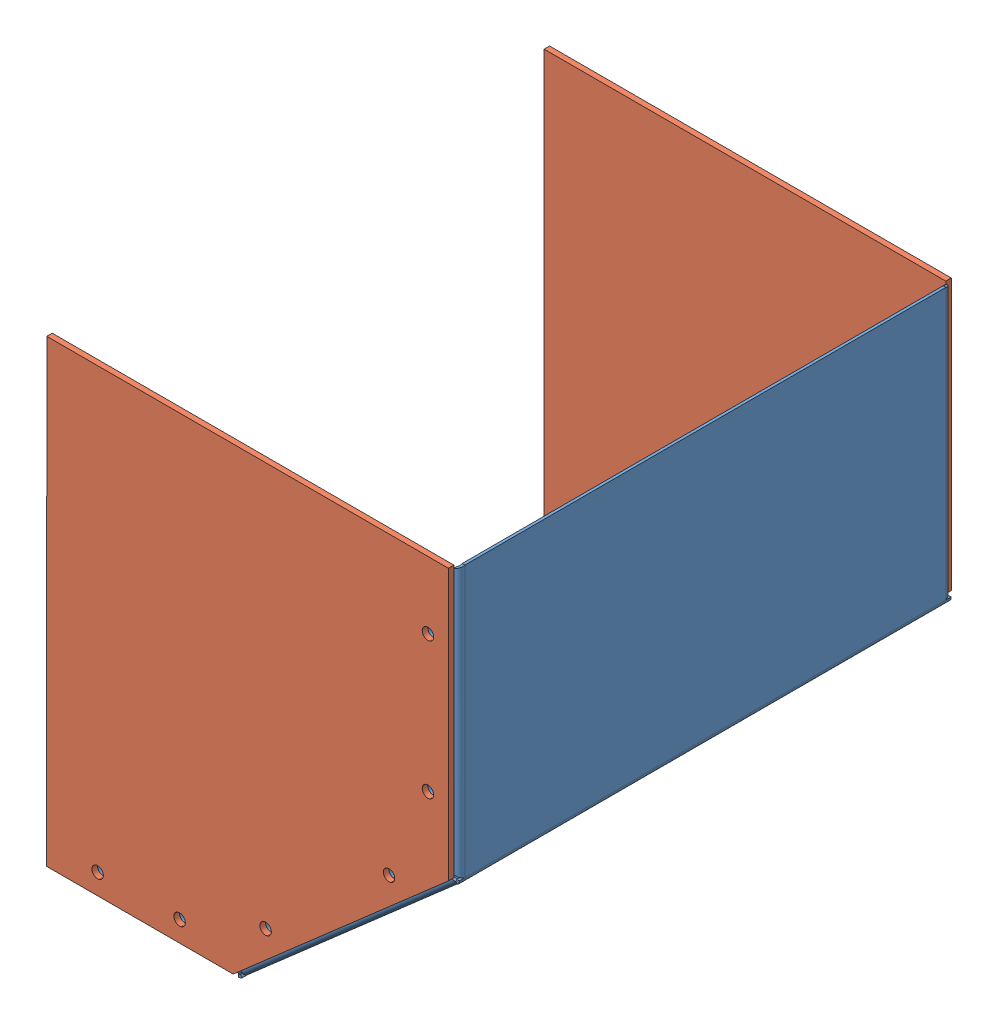
SolidWorks assembly (改)取り出し口周辺, configuration ﾃﾞﾌｫﾙﾄ. Lengths in mm.
Overall size (150.12 170.12 184).
3 component instances, 3 part files, 6 mates.
Components (placement in the parent):
- (改)取り出し口正面-1: (改)取り出し口正面 [ﾃﾞﾌｫﾙﾄ] at (41.7532 91.9634 180.2484) size (150.12 170.12 180.25)
- (改)取り出し口右側面-1: (改)取り出し口右側面 [ﾃﾞﾌｫﾙﾄ] at (-107.2486 -64.9092 270.2484) x (1 -0.000067 0) z (0 0 1) size (146.99 168.01 2)
- (改)取り出し口側面-2: (改)取り出し口側面 [ﾃﾞﾌｫﾙﾄ] at (-107.243 -64.9029 88.2484) x (1 -0.000067 0) z (0 0 1) size (146.99 168.01 2)
Mates (geometry in assembly coordinates):
- 同心円1: concentric: cylinder of (改)取り出し口正面-1 through (32.2532 78.5496 90.1242) axis (0 0 1) radius 2.1; cylinder of (改)取り出し口右側面-1 through (32.2532 78.5496 272.2484) axis (0 0 -1) radius 2.1
- 同心円7: concentric: circle of (改)取り出し口右側面-1; circle of (改)取り出し口正面-1
- 一致1: coincident: plane of (改)取り出し口正面-1 through (41.7532 91.9634 270.2484) normal (0 0 1); plane of (改)取り出し口右側面-1 through (-107.2486 -64.9092 270.2484) normal (0 0 -1)
- 同心円3: concentric: cylinder of (改)取り出し口正面-1 through (-88.6225 -57.4041 90.1242) axis (0 0 1) radius 2.1; cylinder of (改)取り出し口側面-2 through (-88.6225 -57.4041 90.2484) axis (0 0 -1) radius 2.1
- 同心円10: concentric: circle of (改)取り出し口正面-1; circle of (改)取り出し口側面-2
- 一致3: coincident: plane of (改)取り出し口正面-1 through (41.7532 91.9634 90.2484) normal (0 0 -1); plane of (改)取り出し口側面-2 through (-107.243 -64.9029 90.2484) normal (0 0 1)
